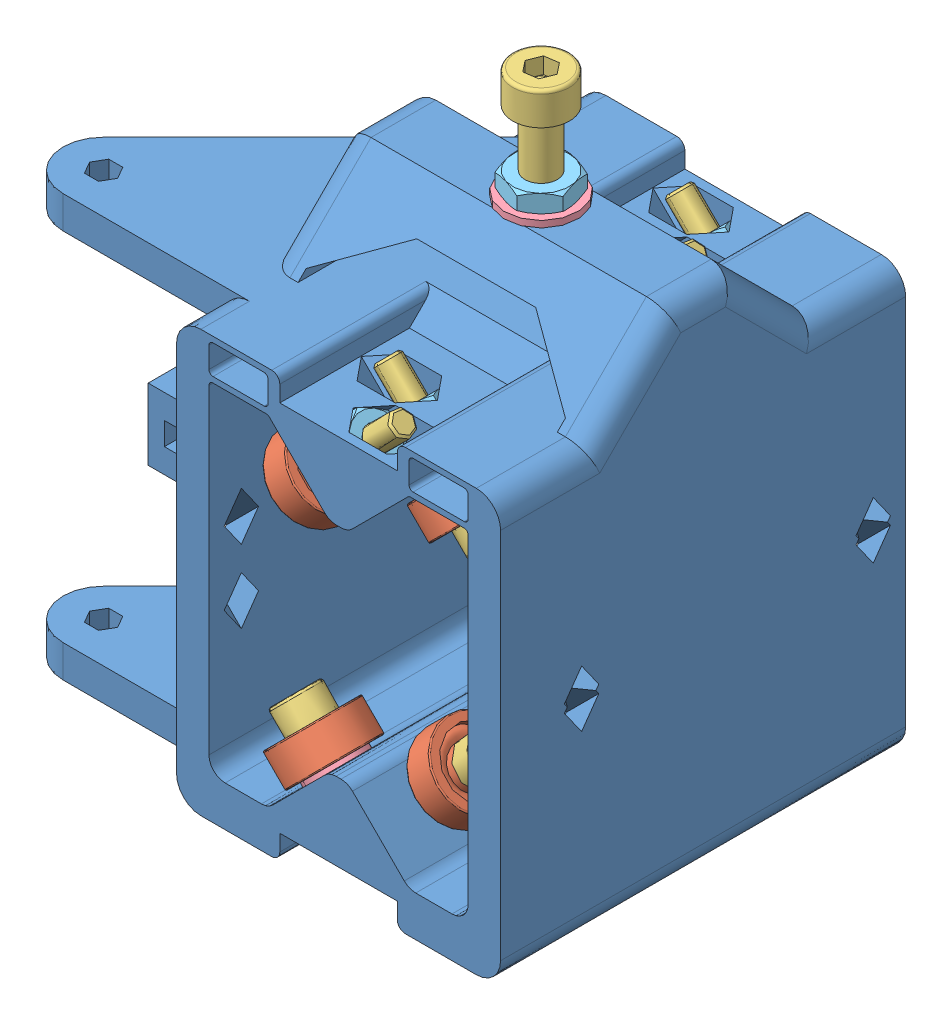
SolidWorks assembly Carriage Assy, configuration Default. Lengths in mm.
Overall size (65 86.21 59.4).
41 component instances, 6 part files, 31 mates.
Components (placement in the parent):
- Carriage-1: Carriage [Default] at (0 0 320.5283) size (65 71.5 50)
- radial ball bearing_68_skf-3: radial ball bearing_68_skf [SKF - 623 - 8,SI,NC,8_68] at (5.869 -14.6371 299.5283) x (-0.707107 -0.707107 0) z (0.665008 -0.665008 -0.339896) size (4 10 10)
- socket head cap screw 4762_din-1: socket head cap screw 4762_din [ISO 4762 M3 x 16 --- 16N] at (9.4045 -11.1016 299.5283) x (-0.707107 -0.707107 0) z (0.494843 -0.494843 -0.714325) size (19 5.5 5.5)
- plain washer grade a_din-1: plain washer grade a_din [Washer DIN 125 - A 3.2] at (4.4548 -16.0513 299.5283) x (0.707107 0.707107 0) z (0 0 1) size (0.5 7 7)
- hex thin nut chamfered gradeab_din-1: hex thin nut chamfered gradeab_din [Hexagon Thin Nut ISO 4035 - M3 - N] at (-0.7071 -21.2132 299.5283) x (0.612372 -0.612372 -0.5) z (-0.707107 -0.707107 0) size (5.5 6.35 1.8)
- socket head cap screw 4762_din-2: socket head cap screw 4762_din [ISO 4762 M3 x 16 --- 16N] at (9.4045 -11.1016 335.5283) x (-0.707107 -0.707107 0) z (0.494843 -0.494843 -0.714325) size (19 5.5 5.5)
- hex thin nut chamfered gradeab_din-3: hex thin nut chamfered gradeab_din [Hexagon Thin Nut ISO 4035 - M3 - N] at (-0.7071 -21.2132 335.5283) x (0.612372 -0.612372 -0.5) z (-0.707107 -0.707107 0) size (5.5 6.35 1.8)
- radial ball bearing_68_skf-4: radial ball bearing_68_skf [SKF - 623 - 8,SI,NC,8_68] at (5.869 -14.6371 335.5283) x (-0.707107 -0.707107 0) z (0.665008 -0.665008 -0.339896) size (4 10 10)
- plain washer grade a_din-2: plain washer grade a_din [Washer DIN 125 - A 3.2] at (4.4548 -16.0513 335.5283) x (0.707107 0.707107 0) z (0 0 1) size (0.5 7 7)
- socket head cap screw 4762_din-3: socket head cap screw 4762_din [ISO 4762 M3 x 16 --- 16N] at (-9.4045 -11.1016 341.5283) x (0.707107 -0.707107 0) z (-0.494843 -0.494843 0.714325) size (19 5.5 5.5)
- hex thin nut chamfered gradeab_din-4: hex thin nut chamfered gradeab_din [Hexagon Thin Nut ISO 4035 - M3 - N] at (0.7071 -21.2132 341.5283) x (-0.612372 -0.612372 0.5) z (0.707107 -0.707107 0) size (5.5 6.35 1.8)
- radial ball bearing_68_skf-5: radial ball bearing_68_skf [SKF - 623 - 8,SI,NC,8_68] at (-5.869 -14.6371 341.5283) x (0.707107 -0.707107 0) z (-0.665008 -0.665008 0.339896) size (4 10 10)
- plain washer grade a_din-3: plain washer grade a_din [Washer DIN 125 - A 3.2] at (-4.4548 -16.0513 341.5283) x (-0.707107 0.707107 0) z (0 0 -1) size (0.5 7 7)
- socket head cap screw 4762_din-4: socket head cap screw 4762_din [ISO 4762 M3 x 16 --- 16N] at (-9.4045 -11.1016 305.5283) x (0.707107 -0.707107 0) z (-0.494843 -0.494843 0.714325) size (19 5.5 5.5)
- hex thin nut chamfered gradeab_din-5: hex thin nut chamfered gradeab_din [Hexagon Thin Nut ISO 4035 - M3 - N] at (0.7071 -21.2132 305.5283) x (-0.612372 -0.612372 0.5) z (0.707107 -0.707107 0) size (5.5 6.35 1.8)
- radial ball bearing_68_skf-6: radial ball bearing_68_skf [SKF - 623 - 8,SI,NC,8_68] at (-5.869 -14.6371 305.5283) x (0.707107 -0.707107 0) z (-0.665008 -0.665008 0.339896) size (4 10 10)
- plain washer grade a_din-4: plain washer grade a_din [Washer DIN 125 - A 3.2] at (-4.4548 -16.0513 305.5283) x (-0.707107 0.707107 0) z (0 0 -1) size (0.5 7 7)
- socket head cap screw 4762_din-5: socket head cap screw 4762_din [ISO 4762 M3 x 16 --- 16N] at (9.4045 11.1016 335.5283) x (-0.707107 0.707107 0) z (-0.494843 -0.494843 0.714325) size (19 5.5 5.5)
- hex thin nut chamfered gradeab_din-6: hex thin nut chamfered gradeab_din [Hexagon Thin Nut ISO 4035 - M3 - N] at (0.564 19.9421 335.5283) x (0.612372 0.612372 -0.5) z (0.707107 -0.707107 0) size (5.5 6.35 1.8)
- radial ball bearing_68_skf-7: radial ball bearing_68_skf [SKF - 623 - 8,SI,NC,8_68] at (5.869 14.6371 335.5283) x (-0.707107 0.707107 0) z (-0.665008 -0.665008 0.339896) size (4 10 10)
- plain washer grade a_din-5: plain washer grade a_din [Washer DIN 125 - A 3.2] at (4.4548 16.0513 335.5283) x (0.707107 -0.707107 0) z (0 0 -1) size (0.5 7 7)
- socket head cap screw 4762_din-6: socket head cap screw 4762_din [ISO 4762 M3 x 16 --- 16N] at (-9.4045 11.1016 341.5283) x (0.707107 0.707107 0) z (0.494843 -0.494843 -0.714325) size (19 5.5 5.5)
- hex thin nut chamfered gradeab_din-7: hex thin nut chamfered gradeab_din [Hexagon Thin Nut ISO 4035 - M3 - N] at (-0.564 19.9421 341.5283) x (-0.612372 0.612372 0.5) z (-0.707107 -0.707107 0) size (5.5 6.35 1.8)
- radial ball bearing_68_skf-8: radial ball bearing_68_skf [SKF - 623 - 8,SI,NC,8_68] at (-5.869 14.6371 341.5283) x (0.707107 0.707107 0) z (0.665008 -0.665008 -0.339896) size (4 10 10)
- plain washer grade a_din-6: plain washer grade a_din [Washer DIN 125 - A 3.2] at (-4.4548 16.0513 341.5283) x (-0.707107 -0.707107 0) z (0 0 1) size (0.5 7 7)
- socket head cap screw 4762_din-7: socket head cap screw 4762_din [ISO 4762 M3 x 16 --- 16N] at (-9.4045 11.1016 305.5283) x (0.707107 0.707107 0) z (0.494843 -0.494843 -0.714325) size (19 5.5 5.5)
- hex thin nut chamfered gradeab_din-8: hex thin nut chamfered gradeab_din [Hexagon Thin Nut ISO 4035 - M3 - N] at (-0.564 19.9421 305.5283) x (-0.612372 0.612372 0.5) z (-0.707107 -0.707107 0) size (5.5 6.35 1.8)
- radial ball bearing_68_skf-9: radial ball bearing_68_skf [SKF - 623 - 8,SI,NC,8_68] at (-5.869 14.6371 305.5283) x (0.707107 0.707107 0) z (0.665008 -0.665008 -0.339896) size (4 10 10)
- plain washer grade a_din-7: plain washer grade a_din [Washer DIN 125 - A 3.2] at (-4.4548 16.0513 305.5283) x (-0.707107 -0.707107 0) z (0 0 1) size (0.5 7 7)
- hex thin nut chamfered gradeab_din-9: hex thin nut chamfered gradeab_din [Hexagon Thin Nut ISO 4035 - M3 - N] at (0.564 19.9421 299.5283) x (0.612372 0.612372 -0.5) z (0.707107 -0.707107 0) size (5.5 6.35 1.8)
- socket head cap screw 4762_din-8: socket head cap screw 4762_din [ISO 4762 M3 x 16 --- 16N] at (9.4045 11.1016 299.5283) x (-0.707107 0.707107 0) z (-0.494843 -0.494843 0.714325) size (19 5.5 5.5)
- radial ball bearing_68_skf-10: radial ball bearing_68_skf [SKF - 623 - 8,SI,NC,8_68] at (5.869 14.6371 299.5283) x (-0.707107 0.707107 0) z (-0.665008 -0.665008 0.339896) size (4 10 10)
- hex thin nut chamfered gradeab_din-10: hex thin nut chamfered gradeab_din [Hexagon Thin Nut ISO 4035 - M4 - N] at (0 29 320.5283) x (0.996678 0 0.081445) z (0 -1 0) size (7 8.08 2.2)
- socket head cap screw 4762_din-9: socket head cap screw 4762_din [ISO 4762 M4 x 20 --- 20N] at (0 50 320.5283) x (0 -1 0) z (-0.929203 0 -0.369569) size (24 7 7)
- plain washer grade a_din-8: plain washer grade a_din [Washer DIN 125 - A 4.3] at (0 31.2 320.5283) x (0 -1 0) z (-0.172888 0 -0.984942) size (0.8 9 9)
- hex thin nut chamfered gradeab_din-11: hex thin nut chamfered gradeab_din [Hexagon Thin Nut ISO 4035 - M4 - N] at (0 36.8 320.5283) x (-0.973232 0 0.229826) z (0 -1 0) size (7 8.08 2.2)
- plain washer grade a_din-9: plain washer grade a_din [Washer DIN 125 - A 4.3] at (0 36 320.5283) x (0 -1 0) z (-0.172888 0 -0.984942) size (0.8 9 9)
- plain washer grade a_din-24: plain washer grade a_din [Washer DIN 125 - A 3.2] at (4.4548 16.0513 299.5283) x (0.707107 -0.707107 0) z (0 0 -1) size (0.5 7 7)
- hex screw gradeab_din-1: hex screw gradeab_din [ISO 4017 - M4 x 30-N] at (-11.75 -31 288.5283) x (0 0 1) z (1 0 0) size (32.8 8.08 7)
- hex thin nut chamfered gradeab_din-12: hex thin nut chamfered gradeab_din [Hexagon Thin Nut ISO 4035 - M4 - N] at (-11.75 -31 294.7283) x (-0.973232 0.229826 0) z (0 0 1) size (7 8.08 2.2)
- plain washer grade a_din-25: plain washer grade a_din [Washer DIN 125 - A 4.3] at (-11.75 -31 294.7283) x (0 0 -1) z (-0.172888 0.984942 0) size (0.8 9 9)
Mates (geometry in assembly coordinates):
- Coincident8: coincident aligned: plane of Carriage-1 through (0 0 320.5283) normal (1 0 0); plane of assembly through (0 0 0) normal (1 0 0)
- Coincident9: coincident aligned: plane of Carriage-1 through (0 0 320.5283) normal (0 1 0); plane of assembly through (0 0 0) normal (0 1 0)
- Concentric1: concentric anti-aligned: line of Carriage-1 through (-2.8951 -23.4012 299.5283) axis (0.707107 0.707107 0); cylinder of radial ball bearing_68_skf-3 through (20.4619 -0.0442 299.5283) axis (-0.707107 -0.707107 0) radius 1.5
- Concentric2: concentric aligned: cylinder of radial ball bearing_68_skf-3 through (20.4619 -0.0442 299.5283) axis (-0.707107 -0.707107 0) radius 1.5; cylinder of plain washer grade a_din-1 through (-20.2409 -40.747 299.5283) axis (-0.707107 -0.707107 0) radius 1.6
- Coincident13: coincident anti-aligned: plane of radial ball bearing_68_skf-3 through (4.0582 -15.6548 297.9765) normal (-0.707107 -0.707107 0); plane of plain washer grade a_din-1 through (3.3234 -14.92 299.5283) normal (0.707107 0.707107 0)
- Coincident14: coincident anti-aligned: plane of Carriage-1 through (-6.1518 -6.1518 345.5283) normal (0.707107 0.707107 0); plane of plain washer grade a_din-1 through (1.6263 -13.93 299.5283) normal (-0.707107 -0.707107 0)
- Concentric3: concentric anti-aligned: cylinder of radial ball bearing_68_skf-3 through (20.4619 -0.0442 299.5283) axis (-0.707107 -0.707107 0) radius 1.5; cylinder of socket head cap screw 4762_din-1 through (31.8552 11.3491 299.5283) axis (0.707107 0.707107 0) radius 1.5
- Coincident15: coincident anti-aligned: plane of radial ball bearing_68_skf-3 through (6.6703 -12.61 297.1301) normal (0.707107 0.707107 0); plane of socket head cap screw 4762_din-1 through (5.8942 -11.8339 297.6038) normal (-0.707107 -0.707107 0)
- Concentric5: concentric anti-aligned: cylinder of socket head cap screw 4762_din-1 through (31.8552 11.3491 299.5283) axis (0.707107 0.707107 0) radius 1.5; cylinder of hex thin nut chamfered gradeab_din-1 through (0.5657 -19.9404 299.5283) axis (-0.707107 -0.707107 0) radius 1.25
- Coincident17: coincident anti-aligned: plane of Carriage-1 through (-9.6874 -9.6874 320.5283) normal (-0.707107 -0.707107 0); plane of hex thin nut chamfered gradeab_din-1 through (1.6884 -21.0631 302.2783) normal (0.707107 0.707107 0)
- Parallel2: parallel anti-aligned: plane of Carriage-1 through (-13.9217 -32.0803 302.4033) normal (0 0 -1); plane of hex thin nut chamfered gradeab_din-1 through (1.6884 -21.0631 302.2783) normal (0 0 1)
- Concentric6: concentric anti-aligned: cylinder of socket head cap screw 4762_din-9 through (0 81.75 320.5283) axis (0 1 0) radius 2; cylinder of hex thin nut chamfered gradeab_din-10 through (0 31.2 320.5283) axis (0 -1 0) radius 1.65
- Concentric7: concentric aligned: cylinder of socket head cap screw 4762_din-9 through (0 81.75 320.5283) axis (0 1 0) radius 2; cylinder of plain washer grade a_din-8 through (0 66.125 320.5283) axis (0 1 0) radius 2.15
- Coincident19: coincident anti-aligned: plane of Carriage-1 through (-7.3397 32 295.5283) normal (0 -1 0); plane of plain washer grade a_din-8 through (-4.4322 32 321.3063) normal (0 1 0)
- Coincident20: coincident anti-aligned: plane of hex thin nut chamfered gradeab_din-10 through (-6.9767 31.2 319.9582) normal (0 1 0); plane of plain washer grade a_din-8 through (-2.1176 31.2 320.9) normal (0 -1 0)
- Concentric8: concentric aligned: line of Carriage-1 through (0 31.575 320.5283) axis (0 1 0); cylinder of socket head cap screw 4762_din-9 through (0 81.75 320.5283) axis (0 1 0) radius 2
- Coincident21: coincident anti-aligned: plane of Carriage-1 through (0 26 345.5283) normal (0 1 0); plane of socket head cap screw 4762_din-9 through (-0.595 26 322.0243) normal (0 -1 0)
- Coincident22: coincident anti-aligned: plane of Carriage-1 through (-49.7321 36 316.5283) normal (0 1 0); plane of plain washer grade a_din-9 through (-2.1176 36 320.9) normal (0 -1 0)
- Coincident23: coincident anti-aligned: plane of hex thin nut chamfered gradeab_din-11 through (6.8126 36.8 318.9195) normal (0 -1 0); plane of plain washer grade a_din-9 through (-4.4322 36.8 321.3063) normal (0 1 0)
- Concentric9: concentric aligned: cylinder of socket head cap screw 4762_din-9 through (0 81.75 320.5283) axis (0 1 0) radius 2; cylinder of plain washer grade a_din-9 through (0 70.925 320.5283) axis (0 1 0) radius 2.15
- Concentric10: concentric anti-aligned: cylinder of socket head cap screw 4762_din-9 through (0 81.75 320.5283) axis (0 1 0) radius 2; cylinder of hex thin nut chamfered gradeab_din-11 through (0 39 320.5283) axis (0 -1 0) radius 1.65
- Concentric11: concentric aligned: cylinder of socket head cap screw 4762_din-9 through (0 81.75 320.5283) axis (0 1 0) radius 2; cylinder of plain washer grade a_din-8 through (0 66.125 320.5283) axis (0 1 0) radius 2.15
- Concentric12: concentric anti-aligned: cylinder of hex thin nut chamfered gradeab_din-10 through (0 31.2 320.5283) axis (0 -1 0) radius 1.65; cylinder of socket head cap screw 4762_din-9 through (0 81.75 320.5283) axis (0 1 0) radius 2
- Tangent1: tangent anti-aligned: plane of Carriage-1 through (-2.3094 -26.001 320.5283) normal (0.866025 0 -0.5); cylinder of socket head cap screw 4762_din-9 through (0 81.75 320.5283) axis (0 1 0) radius 2
- Tangent2: tangent anti-aligned: plane of Carriage-1 through (1.1547 -26.001 318.5283) normal (0 0 1); cylinder of socket head cap screw 4762_din-9 through (0 81.75 320.5283) axis (0 1 0) radius 2
- Concentric13: concentric aligned: cylinder of Carriage-1 through (-11.75 -31 305.5283) axis (0 0 -1) radius 1.65; cylinder of hex screw gradeab_din-1 through (-11.75 -31 288.5283) axis (0 0 -1) radius 2
- Distance1: distance = 7 mm aligned: plane of Carriage-1 through (0 0 295.5283) normal (0 0 -1); plane of hex screw gradeab_din-1 through (-11.75 -35.0415 288.5283) normal (0 0 -1)
- Concentric14: concentric anti-aligned: cylinder of hex screw gradeab_din-1 through (-11.75 -31 288.5283) axis (0 0 -1) radius 2; cylinder of plain washer grade a_din-25 through (-11.75 -31 329.6533) axis (0 0 1) radius 2.15
- Concentric15: concentric anti-aligned: cylinder of hex screw gradeab_din-1 through (-11.75 -31 288.5283) axis (0 0 -1) radius 2; cylinder of hex thin nut chamfered gradeab_din-12 through (-11.75 -31 292.5283) axis (0 0 1) radius 1.65
- Coincident25: coincident anti-aligned: plane of hex thin nut chamfered gradeab_din-12 through (-4.9374 -32.6088 294.7283) normal (0 0 1); plane of plain washer grade a_din-25 through (-13.8676 -31.3717 294.7283) normal (0 0 -1)
- Coincident26: coincident anti-aligned: plane of Carriage-1 through (0 0 295.5283) normal (0 0 -1); plane of plain washer grade a_din-25 through (-16.1822 -31.778 295.5283) normal (0 0 1)
